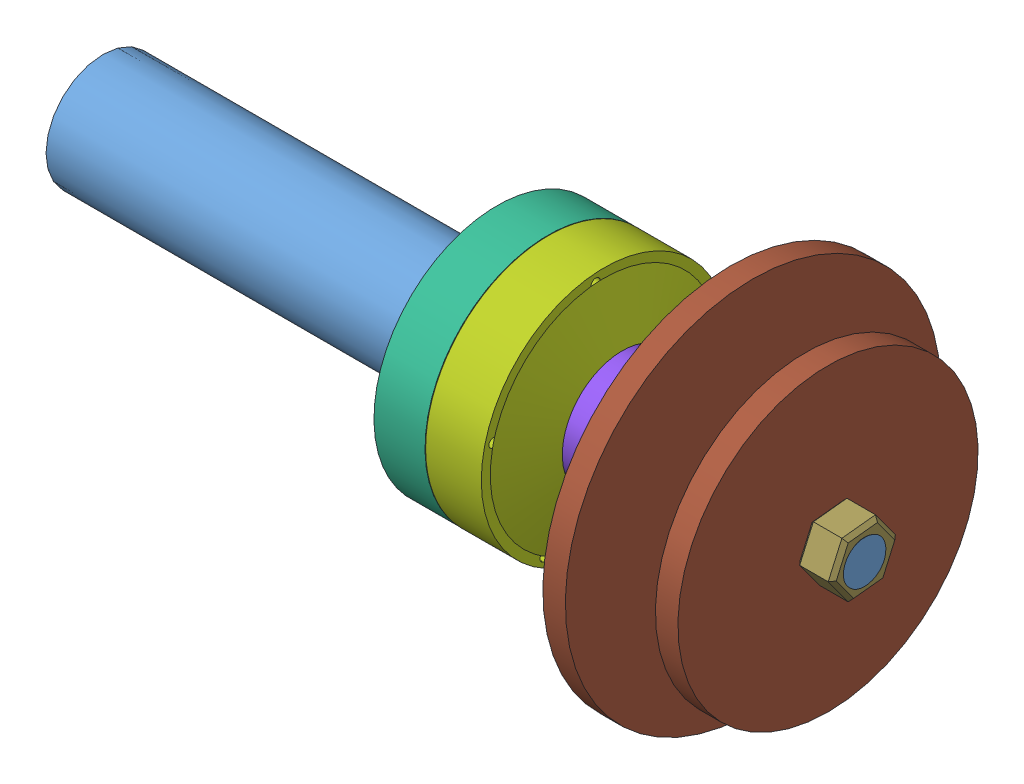
SolidWorks assembly shaft_assembly, configuration Default. Lengths in mm.
Overall size (1018.05 517.94 517.94).
44 component instances, 13 part files, 20 mates.
Components (placement in the parent):
- shaft-1: shaft [Default] at origin size (1018.05 152 152)
- SKF_22324_CCJA_W33VA406-1: SKF_22324_CCJA_W33VA406 [Default] at (550 0 0) x (1 0 0) z (0 -0.33773 0.941243) size (86 260 260)
  - SKF_22324_CCJA_W33VA406_3-15: SKF_22324_CCJA_W33VA406_3 [Default] at origin size (39.61 38.72 35)
  - SKF_22324_CCJA_W33VA406_5-15: SKF_22324_CCJA_W33VA406_5 [Default] at origin size (39.74 40.32 35)
  - SKF_22324_CCJA_W33VA406_35-1: SKF_22324_CCJA_W33VA406_35 [Default] at origin size (86 260 260)
  - SKF_22324_CCJA_W33VA406_37-1: SKF_22324_CCJA_W33VA406_37 [Default] at origin size (86 167.02 167.02)
  - SKF_22324_CCJA_W33VA406_3-16: SKF_22324_CCJA_W33VA406_3 [Default] x (1 0 0) z (0 -0.382683 0.92388) size (39.61 38.72 35)
  - SKF_22324_CCJA_W33VA406_3-17: SKF_22324_CCJA_W33VA406_3 [Default] x (1 0 0) z (0 -0.707107 0.707107) size (39.61 38.72 35)
  - SKF_22324_CCJA_W33VA406_3-18: SKF_22324_CCJA_W33VA406_3 [Default] x (1 0 0) z (0 -0.92388 0.382683) size (39.61 38.72 35)
  - SKF_22324_CCJA_W33VA406_3-19: SKF_22324_CCJA_W33VA406_3 [Default] x (1 0 0) z (0 -1 0) size (39.61 38.72 35)
  - SKF_22324_CCJA_W33VA406_3-20: SKF_22324_CCJA_W33VA406_3 [Default] x (1 0 0) z (0 -0.92388 -0.382683) size (39.61 38.72 35)
  - SKF_22324_CCJA_W33VA406_3-21: SKF_22324_CCJA_W33VA406_3 [Default] x (1 0 0) z (0 -0.707107 -0.707107) size (39.61 38.72 35)
  - SKF_22324_CCJA_W33VA406_3-22: SKF_22324_CCJA_W33VA406_3 [Default] x (1 0 0) z (0 -0.382683 -0.92388) size (39.61 38.72 35)
  - SKF_22324_CCJA_W33VA406_3-23: SKF_22324_CCJA_W33VA406_3 [Default] x (1 0 0) z (0 0 -1) size (39.61 38.72 35)
  - SKF_22324_CCJA_W33VA406_3-24: SKF_22324_CCJA_W33VA406_3 [Default] x (1 0 0) z (0 0.382683 -0.92388) size (39.61 38.72 35)
  - SKF_22324_CCJA_W33VA406_3-25: SKF_22324_CCJA_W33VA406_3 [Default] x (1 0 0) z (0 0.707107 -0.707107) size (39.61 38.72 35)
  - SKF_22324_CCJA_W33VA406_3-26: SKF_22324_CCJA_W33VA406_3 [Default] x (1 0 0) z (0 0.92388 -0.382683) size (39.61 38.72 35)
  - SKF_22324_CCJA_W33VA406_3-27: SKF_22324_CCJA_W33VA406_3 [Default] x (1 0 0) z (0 1 0) size (39.61 38.72 35)
  - SKF_22324_CCJA_W33VA406_3-28: SKF_22324_CCJA_W33VA406_3 [Default] x (1 0 0) z (0 0.92388 0.382683) size (39.61 38.72 35)
  - SKF_22324_CCJA_W33VA406_3-29: SKF_22324_CCJA_W33VA406_3 [Default] x (1 0 0) z (0 0.707107 0.707107) size (39.61 38.72 35)
  - SKF_22324_CCJA_W33VA406_3-30: SKF_22324_CCJA_W33VA406_3 [Default] x (1 0 0) z (0 0.382683 0.92388) size (39.61 38.72 35)
  - SKF_22324_CCJA_W33VA406_5-16: SKF_22324_CCJA_W33VA406_5 [Default] x (1 0 0) z (0 -0.382683 0.92388) size (39.74 40.32 35)
  - SKF_22324_CCJA_W33VA406_5-17: SKF_22324_CCJA_W33VA406_5 [Default] x (1 0 0) z (0 -0.707107 0.707107) size (39.74 40.32 35)
  - SKF_22324_CCJA_W33VA406_5-18: SKF_22324_CCJA_W33VA406_5 [Default] x (1 0 0) z (0 -0.92388 0.382683) size (39.74 40.32 35)
  - SKF_22324_CCJA_W33VA406_5-19: SKF_22324_CCJA_W33VA406_5 [Default] x (1 0 0) z (0 -1 0) size (39.74 40.32 35)
  - SKF_22324_CCJA_W33VA406_5-20: SKF_22324_CCJA_W33VA406_5 [Default] x (1 0 0) z (0 -0.92388 -0.382683) size (39.74 40.32 35)
  - SKF_22324_CCJA_W33VA406_5-21: SKF_22324_CCJA_W33VA406_5 [Default] x (1 0 0) z (0 -0.707107 -0.707107) size (39.74 40.32 35)
  - SKF_22324_CCJA_W33VA406_5-22: SKF_22324_CCJA_W33VA406_5 [Default] x (1 0 0) z (0 -0.382683 -0.92388) size (39.74 40.32 35)
  - SKF_22324_CCJA_W33VA406_5-23: SKF_22324_CCJA_W33VA406_5 [Default] x (1 0 0) z (0 0 -1) size (39.74 40.32 35)
  - SKF_22324_CCJA_W33VA406_5-24: SKF_22324_CCJA_W33VA406_5 [Default] x (1 0 0) z (0 0.382683 -0.92388) size (39.74 40.32 35)
  - SKF_22324_CCJA_W33VA406_5-25: SKF_22324_CCJA_W33VA406_5 [Default] x (1 0 0) z (0 0.707107 -0.707107) size (39.74 40.32 35)
  - SKF_22324_CCJA_W33VA406_5-26: SKF_22324_CCJA_W33VA406_5 [Default] x (1 0 0) z (0 0.92388 -0.382683) size (39.74 40.32 35)
  - SKF_22324_CCJA_W33VA406_5-27: SKF_22324_CCJA_W33VA406_5 [Default] x (1 0 0) z (0 1 0) size (39.74 40.32 35)
  - SKF_22324_CCJA_W33VA406_5-28: SKF_22324_CCJA_W33VA406_5 [Default] x (1 0 0) z (0 0.92388 0.382683) size (39.74 40.32 35)
  - SKF_22324_CCJA_W33VA406_5-29: SKF_22324_CCJA_W33VA406_5 [Default] x (1 0 0) z (0 0.707107 0.707107) size (39.74 40.32 35)
  - SKF_22324_CCJA_W33VA406_5-30: SKF_22324_CCJA_W33VA406_5 [Default] x (1 0 0) z (0 0.382683 0.92388) size (39.74 40.32 35)
- casing_back-1: casing_back [Default] at (550 0 0) x (1 0 0) z (0 0.873261 -0.487252) size (93 328 328)
- casing_front-1: casing_front [Default] at (593 0 0) x (1 0 0) z (0 0.924625 0.38088) size (98.99 328 328)
- spacer_ring-1: spacer_ring [Default] at (836 0 0) x (0 0.929144 0.369718) z (-1 0 0) size (140 140 200)
- mounting_plate-1: mounting_plate [Default] at (515 0 0) x (0 -0.107034 -0.994255) z (1 0 0) size (500 500 10) (hidden)
- SKF_140X160X12_HMS5_V-1: SKF_140X160X12_HMS5_V [Default] at (655.9977 0 0) x (1 0 0) z (0 -0.027042 0.999634) size (12 160 160)
- SKF_60000-2: SKF_60000 [Default] at (537.3 0 0) size (12.7 171.45 171.45)
- pulley_coupling_flange-1: pulley_coupling_flange [Default] at (867.9421 5.8206 0.2129) x (0 0.036554 -0.999332) z (-1 0 0) size (500 500 130)
- m60_nut-1: m60_nut [Default] at (1016 0 0) x (0 -0.105986 0.994368) z (-1 0 0) size (90 77.94 52.04)
Mates (geometry in assembly coordinates):
- Concentric1: concentric anti-aligned: cylinder of shaft-1 through (936 0 0) axis (-1 0 0) radius 60; cylinder of SKF_22324_CCJA_W33VA406-1/SKF_22324_CCJA_W33VA406_37-1 through (636 0 0) axis (1 0 0) radius 60
- Coincident1: coincident anti-aligned: plane of shaft-1 through (550 0 0) normal (1 0 0); plane of SKF_22324_CCJA_W33VA406-1/SKF_22324_CCJA_W33VA406_37-1 through (550 71.5345 25.6675) normal (-1 0 0)
- Coincident2: coincident anti-aligned: plane of SKF_22324_CCJA_W33VA406-1/SKF_22324_CCJA_W33VA406_35-1 through (550 119.5379 42.8917) normal (-1 0 0); plane of casing_back-1 through (550 0 0) normal (1 0 0)
- Concentric3: concentric aligned: cylinder of shaft-1 through (936 0 0) axis (-1 0 0) radius 60; cylinder of casing_front-1 through (593 0 0) axis (-1 0 0) radius 80
- Concentric4: concentric anti-aligned: cylinder of shaft-1 through (936 0 0) axis (-1 0 0) radius 60; cylinder of spacer_ring-1 through (636 0 0) axis (1 0 0) radius 60
- Coincident4: coincident anti-aligned: plane of SKF_22324_CCJA_W33VA406-1/SKF_22324_CCJA_W33VA406_37-1 through (636 63 0) normal (1 0 0); plane of spacer_ring-1 through (636 0 0) normal (-1 0 0)
- Coincident5: coincident anti-aligned: plane of SKF_22324_CCJA_W33VA406-1/SKF_22324_CCJA_W33VA406_37-1 through (636 59.2983 21.277) normal (1 0 0); plane of spacer_ring-1 through (636 0 0) normal (-1 0 0)
- Coincident6: coincident anti-aligned: plane of casing_back-1 through (593 0 0) normal (1 0 0); plane of casing_front-1 through (593 0 0) normal (-1 0 0)
- Concentric5: concentric: circle of casing_back-1; circle of casing_front-1
- Concentric6: concentric anti-aligned: cylinder of casing_back-1 through (650.2885 0 0) axis (1 0 0) radius 88.25; cylinder of mounting_plate-1 through (525 0 0) axis (-1 0 0) radius 88.25
- Coincident7: coincident anti-aligned: plane of casing_back-1 through (525 0 0) normal (-1 0 0); plane of mounting_plate-1 through (525 0 0) normal (1 0 0)
- Concentric8: concentric anti-aligned: cylinder of casing_back-1 through (650.2885 0 0) axis (1 0 0) radius 140; cylinder of casing_front-1 through (593 0 0) axis (-1 0 0) radius 140
- Concentric10: concentric anti-aligned: cylinder of casing_front-1 through (593 0 0) axis (-1 0 0) radius 80; cylinder of SKF_140X160X12_HMS5_V-1 through (667.9977 0 0) axis (1 0 0) radius 80
- Coincident10: coincident anti-aligned: plane of casing_front-1 through (655.9977 0 0) normal (1 0 0); plane of SKF_140X160X12_HMS5_V-1 through (655.9977 79.9707 2.1634) normal (-1 0 0)
- Coincident12: coincident anti-aligned: plane of casing_back-1 through (537.3 0 0) normal (1 0 0); plane of SKF_60000-2 through (537.3 84.775 0) normal (-1 0 0)
- Concentric12: concentric aligned: cylinder of casing_back-1 through (650.2885 0 0) axis (1 0 0) radius 85.73; cylinder of SKF_60000-2 through (587.3 0 0) axis (1 0 0) radius 85.725
- Concentric14: concentric aligned: cylinder of shaft-1 through (936 0 0) axis (-1 0 0) radius 60; cylinder of pulley_coupling_flange-1 through (867.9421 0 0) axis (-1 0 0) radius 60
- Coincident14: coincident anti-aligned: plane of spacer_ring-1 through (836 0 0) normal (1 0 0); plane of pulley_coupling_flange-1 through (836 -59.9599 -2.1932) normal (-1 0 0)
- Coincident15: coincident aligned: plane of shaft-1 through (1016 0 0) normal (1 0 0); plane of m60_nut-1 through (1016 0 0) normal (1 0 0)
- Concentric16: concentric aligned: circle of shaft-1; circle of m60_nut-1
